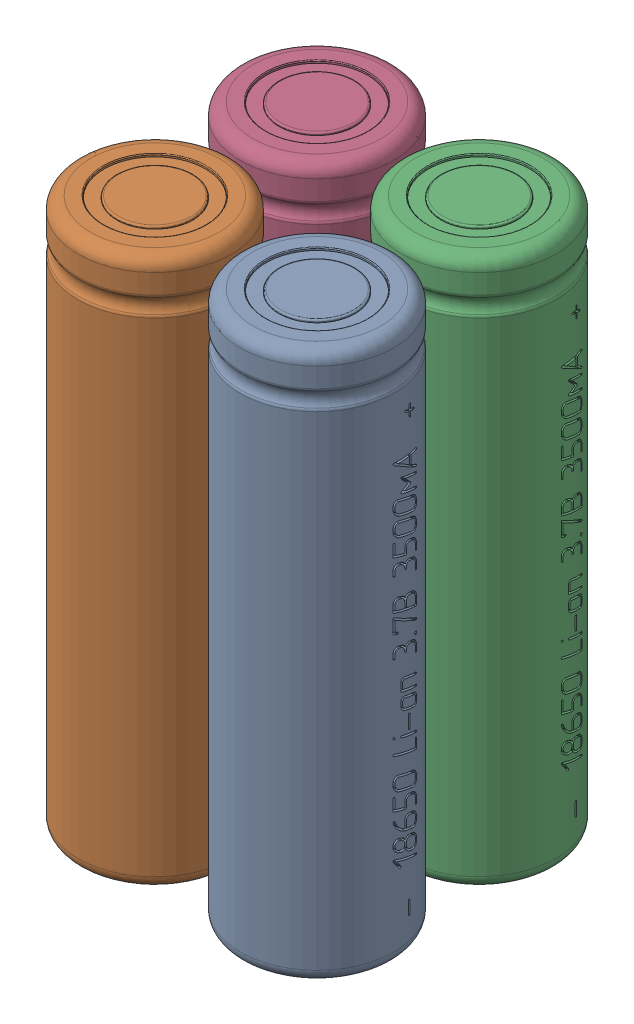
SolidWorks assembly battery_pack4, configuration Default. Lengths in mm.
Overall size (43.06 65 42.58).
4 component instances, 1 part files, 8 mates.
Components (placement in the parent):
- 18650-9: 18650 [По умолчанию] x (0 1 0) z (0.957422 0 -0.288693) size (65 18.2 18.21)
- 18650-10: 18650 [По умолчанию] at (-19.2128 0 0) x (0 1 0) z (-0.99989 0 0.014848) size (65 18.2 18.21)
- 18650-14: 18650 [По умолчанию] at (0 0 -19.2128) x (0 1 0) z (0.930271 0 -0.366873) size (65 18.2 18.21)
- 18650-15: 18650 [По умолчанию] at (-19.2128 0 -19.2128) x (0 1 0) z (-0.91235 0 0.409412) size (65 18.2 18.21)
Mates (geometry in assembly coordinates):
- Coincident20: coincident: point of 18650-9; point of assembly
- Coincident21: coincident anti-aligned: plane of 18650-9 through (0 0 0) normal (0 -1 0)
- Coincident22: coincident: point of 18650-10; point of assembly
- Coincident23: coincident anti-aligned: plane of 18650-10 through (-19.2128 0 0) normal (0 -1 0)
- Coincident30: coincident: point of 18650-14; point of assembly
- Coincident31: coincident anti-aligned: plane of 18650-14 through (0 0 -19.2128) normal (0 -1 0)
- Coincident34: coincident: point of 18650-15; point of assembly
- Coincident35: coincident anti-aligned: plane of 18650-15 through (-19.2128 0 -19.2128) normal (0 -1 0)
